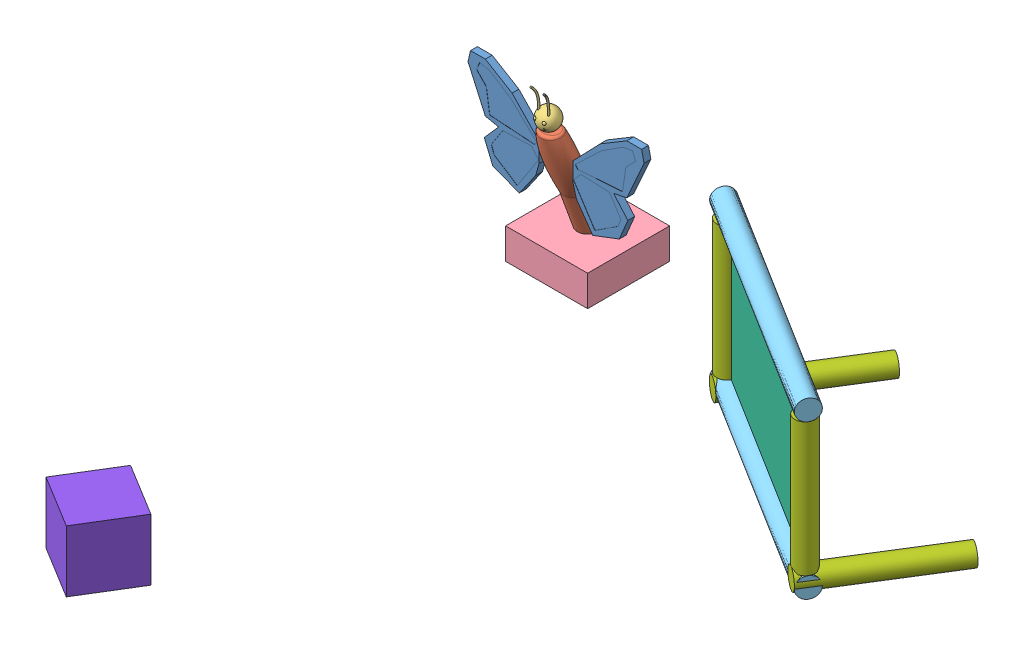
SolidWorks assembly scene, configuration Default. Lengths in mm.
Overall size (10972.8 4942.67 10972.8).
16 component instances, 8 part files, 2 mates.
Components (placement in the parent):
- butterfly_base-1: butterfly_base [Default] at (927.0193 1328.2068 2061.1042) size (2617.43 2571.07 1359.12)
  - butterfly-1: butterfly [Default] at (954.3499 1641.3317 1833.9497) size (2617.43 2113.87 901.92)
    - Wing-1: Wing [Default] at (371.665 221.4807 1594.4083) size (1207.07 1471.46 101.61)
    - Body-1: Body [Default] at (625.7054 -140.7403 1226.9822) size (574.9 1524 859.04)
    - Wing-2: Wing [Default] at (879.7459 221.4807 1696.0083) x (-1 0 0) z (0 0 -1) size (1207.07 1471.46 101.61)
    - Head-1: Head [Default] at (619.7065 1535.6597 1803.3329) size (304.8 589.87 325.57)
  - Base-1: Base [Default] at (1580.0553 1043.3914 3060.932) size (1219.2 457.2 1269.48)
- screen_inflate-1: screen_inflate [Default] at (2427.9139 5269.4365 6767.3645) x (0.529919 0 -0.848048) z (0 -1 0) size (1981.2 4049.37 2671.43)
  - screen_horiz-1: screen_horiz [Default] at (2411.4959 1330.6716 3050.2383) size (304.8 3962.4 304.8)
  - screen_guts-1: screen_guts [Default] at (2449.8766 1635.4716 916.6383) x (0 1 0) z (0 0 1) size (3352.8 25.4 1981.2)
  - screen_vert-1: screen_vert [Default] at (2411.4959 5140.6716 2897.8383) x (-1 0 0) z (0 -1 0) size (304.8 1981.2 304.8)
  - screen_vert-2: screen_vert [Default] at (2411.4959 1483.0716 2897.8383) x (-1 0 0) z (0 -1 0) size (304.8 1981.2 304.8)
  - screen_horiz-2: screen_horiz [Default] at (2411.4959 1330.6716 764.2383) size (304.8 3962.4 304.8)
  - screen_vert-3: screen_vert [Default] at (2259.0959 5147.0071 3006.7534) x (0 -0.285334 0.958428) z (0 0.958428 0.285334) size (304.8 1981.2 304.8)
  - screen_vert-4: screen_vert [Default] at (2259.0959 1476.736 3093.7232) x (0 -0.285334 0.958428) z (0 0.958428 0.285334) size (304.8 1981.2 304.8)
- projector_box-1: projector_box [Default] at (2650.1754 2371.5982 12060.091) x (0.85264 0 0.522499) z (-0.522499 0 0.85264) size (914.4 914.4 914.4)
Mates (geometry in assembly coordinates):
- Tangent1: tangent: plane of butterfly_base-1/Base-1 through (2507.0747 2371.5982 5122.0361) normal (0 -1 0); cylinder of screen_inflate-1/screen_horiz-1 through (8194.5913 2219.1982 7527.2006) axis (-0.848048 0 -0.529919) radius 152.4
- Coincident1: coincident: plane of butterfly_base-1/Base-1 through (2507.0747 2371.5982 5122.0361) normal (0 -1 0); plane of projector_box-1 through (2650.1754 2371.5982 12060.091) normal (0 -1 0)
